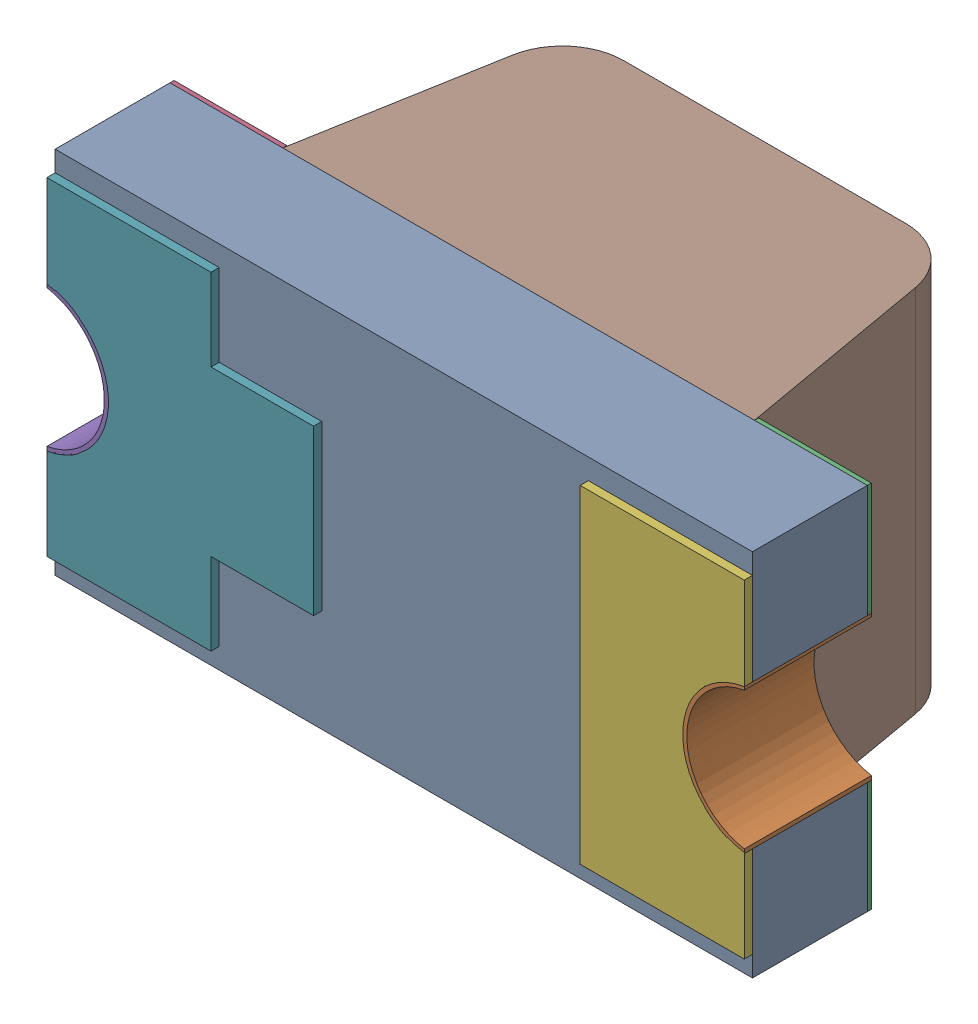
SolidWorks assembly D1摄像头, configuration 默认. Lengths in mm.
Overall size (1.7 0.9 0.9).
7 component instances, 6 part files, 0 mates.
Components (placement in the parent):
- LED-BLUE-0603-1: LED-BLUE-0603 [默认] at (4.4957 5.5045 -0.3912) x (0 1 0) z (0 0 -1) size (0.9 1.7 0.9)
  - User_Library-LTST-C190TBKT_Pad-1: User_Library-LTST-C190TBKT_Pad [默认] at origin size (0.9 1.7 0.28)
  - User_Library-LTST-C190TBKT_Pad005-1: User_Library-LTST-C190TBKT_Pad005 [默认] at origin size (0.35 0.15 0.31)
  - User_Library-LTST-C190TBKT_Pad001-1: User_Library-LTST-C190TBKT_Pad001 [默认] at origin size (0.9 1.7 0.01)
  - User_Library-LTST-C190TBKT_Pad004-1: User_Library-LTST-C190TBKT_Pad004 [默认] at origin size (0.35 0.15 0.31)
  - User_Library-LTST-C190TBKT_Pad003-1: User_Library-LTST-C190TBKT_Pad003 [默认] at origin size (0.8 1.7 0.02)
  - User_Library-LTST-C190TBKT_Lens-1: User_Library-LTST-C190TBKT_Lens [默认] at origin size (0.9 1.15 0.6)
